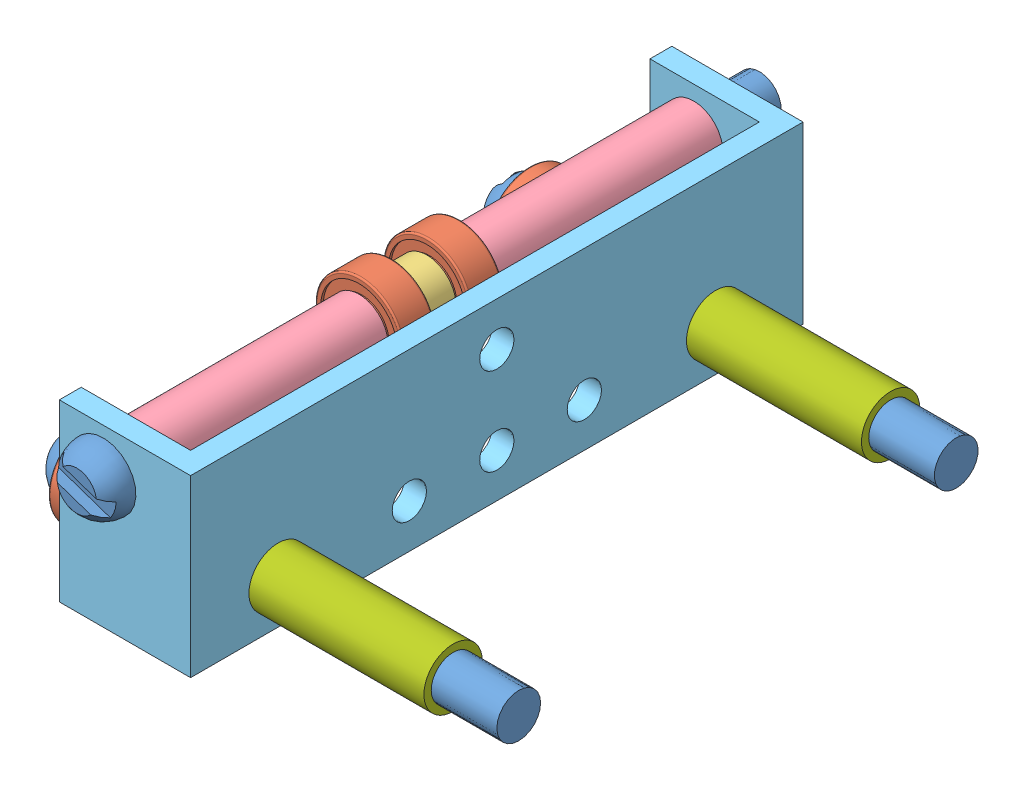
SolidWorks assembly BEARINGASSY, configuration Default. Lengths in mm.
Overall size (65.72 31.8 99.06).
20 component instances, 7 part files, 7 mates.
Components (placement in the parent):
- Elevator_Front_Bearing_Assembly-1: Elevator_Front_Bearing_Assembly [Default] at (-2.3691 57.334 -16.8321) x (-0.322602 -0.946535 0) z (0 0 1) size (17.82 17.82 99.06)
  - .25-20 bolt-1: .25-20 bolt [Default] at (20.9022 42.2675 71.9832) size (9.53 9.53 99.06)
  - Radial_Bearing_0.5_inch-1: Radial_Bearing_0.5_inch [Default] at (20.9022 42.2675 48.3294) x (0 0 -1) z (0.964421 -0.264372 0) size (4.76 12.7 12.7)
  - Radial_Bearing_0.5_inch-2: Radial_Bearing_0.5_inch [Default] at (20.9022 42.2675 38.4869) x (0 0 -1) z (0.788975 0.614426 0) size (4.76 12.7 12.7)
  - Spacer_0.2_inch-2: Spacer_0.2_inch [Default] at (20.9022 42.2675 40.8682) x (0.991317 0.131493 0) z (0 0 1) size (8.47 8.47 5.08)
  - Spacer_inch-1: Spacer_inch [Default] at (20.9022 42.2675 50.7107) x (-0.955936 -0.293574 0) z (0 0 1) size (8.47 8.47 33.97)
  - Spacer_inch-2: Spacer_inch [Default] at (20.9022 42.2675 2.1332) x (-0.332332 -0.943163 0) z (0 0 1) size (8.47 8.47 33.97)
- PLATE-1: PLATE [Default] at (24.5455 4.8637 -17.874) x (0 0 1) z (-1 0 0) size (88.9 25.4 19.05)
- Elevator_Side_Bearing_Assembly-1: Elevator_Side_Bearing_Assembly [Default] at (88.0322 -3.1304 -13.5645) x (0 -0.098071 0.995179) z (-1 0 0) size (14.25 14.25 65.72)
  - .25-20 bolt-1: .25-20 bolt [sHORT] at (6.9434 15.0978 55.5491) size (9.53 9.53 65.72)
  - Radial_Bearing_0.5_inch-1: Radial_Bearing_0.5_inch [Default] at (6.9434 15.0978 69.0429) x (0 0 -1) z (0.028743 -0.999587 0) size (4.76 12.7 12.7)
  - Radial_Bearing_0.5_inch-2: Radial_Bearing_0.5_inch [Default] at (6.9434 15.0978 64.2804) x (0 0 -1) z (0.991417 0.130735 0) size (4.76 12.7 12.7)
  - Spacer_unknown_inch-1: Spacer_unknown_inch [Default] at (6.9434 15.0978 47.6116) size (8.47 8.47 14.29)
  - Spacer_1_inch-1: Spacer_1_inch [Default] at (6.9434 15.0978 19.0366) x (0.031956 -0.999489 0) z (0 0 1) size (8.47 8.47 25.4)
- Elevator_Side_Bearing_Assembly-2: Elevator_Side_Bearing_Assembly [Default] at (88.0322 -3.8841 51.3827) x (0 0 1) z (-1 0 0) size (14.25 14.25 65.72)
  - .25-20 bolt-1: .25-20 bolt [sHORT] at (6.9434 15.0978 55.5491) size (9.53 9.53 65.72)
  - Radial_Bearing_0.5_inch-1: Radial_Bearing_0.5_inch [Default] at (6.9434 15.0978 69.0429) x (0 0 -1) z (0.028743 -0.999587 0) size (4.76 12.7 12.7)
  - Radial_Bearing_0.5_inch-2: Radial_Bearing_0.5_inch [Default] at (6.9434 15.0978 64.2804) x (0 0 -1) z (0.991417 0.130735 0) size (4.76 12.7 12.7)
  - Spacer_unknown_inch-1: Spacer_unknown_inch [Default] at (6.9434 15.0978 47.6116) size (8.47 8.47 14.29)
  - Spacer_1_inch-1: Spacer_1_inch [Default] at (6.9434 15.0978 19.0366) x (0.031956 -0.999489 0) z (0 0 1) size (8.47 8.47 25.4)
Mates (geometry in assembly coordinates):
- Width1: width anti-aligned: plane of Elevator_Front_Bearing_Assembly-1/Radial_Bearing_0.5_inch-1 through (35.4937 20.7947 33.8785) normal (0 0 1); plane of Elevator_Front_Bearing_Assembly-1/Radial_Bearing_0.5_inch-2 through (36.6713 25.9126 19.2735) normal (0 0 -1); plane of PLATE-1 through (24.5455 30.2637 67.851) normal (0 0 -1); plane of PLATE-1 through (40.4205 30.2637 -14.699) normal (0 0 1)
- Concentric2: concentric anti-aligned: cylinder of PLATE-1 through (43.5955 11.2137 -5.174) axis (-1 0 0) radius 3.175; cylinder of Elevator_Side_Bearing_Assembly-1/Spacer_1_inch-1 through (43.5955 11.2137 -5.174) axis (1 0 0) radius 4.2333
- Coincident1: coincident anti-aligned: plane of PLATE-1 through (43.5955 30.2637 -17.874) normal (1 0 0); plane of Elevator_Side_Bearing_Assembly-1/Spacer_1_inch-1 through (43.5955 11.2137 -5.174) normal (-1 0 0)
- Concentric3: concentric anti-aligned: cylinder of PLATE-1 through (43.5955 11.2137 58.326) axis (-1 0 0) radius 3.175; cylinder of Elevator_Side_Bearing_Assembly-2/Spacer_1_inch-1 through (43.5955 11.2137 58.326) axis (1 0 0) radius 4.2333
- Coincident2: coincident anti-aligned: plane of PLATE-1 through (43.5955 30.2637 -17.874) normal (1 0 0); plane of Elevator_Side_Bearing_Assembly-2/Spacer_1_inch-1 through (43.5955 11.2137 58.326) normal (-1 0 0)
- Concentric4: concentric aligned: cylinder of Elevator_Front_Bearing_Assembly-1/.25-20 bolt-1 through (30.8955 23.9137 -24.224) axis (0 0 1) radius 3.175; cylinder of PLATE-1 through (30.8955 23.9137 -17.874) axis (0 0 1) radius 3.175
- Coincident3: coincident anti-aligned: plane of Elevator_Front_Bearing_Assembly-1/.25-20 bolt-1 through (30.8955 23.9137 71.026) normal (0 0 -1); plane of PLATE-1 through (43.5955 30.2637 71.026) normal (0 0 1)
